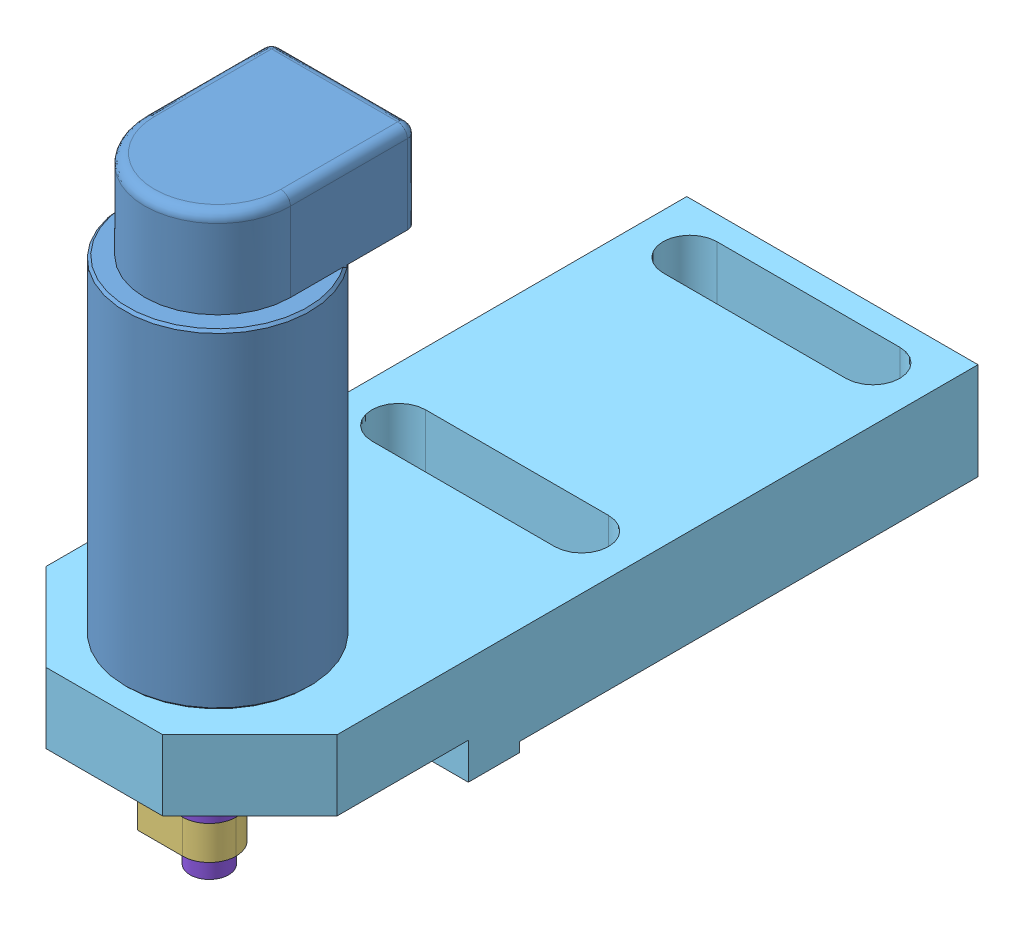
SolidWorks assembly Vibratome Motor Assembly_RevC, configuration Default. Lengths in mm.
Overall size (60 126.02 150).
16 component instances, 8 part files, 33 mates.
Components (placement in the parent):
- [Faulhaber] Series3863MotorwithEncoder-1: [Faulhaber] Series3863MotorwithEncoder [Default] at (-5.4696 226.7867 174.3835) x (1 0 0) z (0 0 -1) size (38 110.4 45.1)
- MotorEshaft-1: MotorEshaft [Default] at (-5.4696 113.4642 187.2942) x (-0.065971 0 0.997822) z (-0.997822 0 -0.065971) size (12.7 33.5 12.7)
- Motor Coupler Rev C-1: Motor Coupler Rev C [Default] at (-11.5224 108.3767 188.0924) x (0 0 1) z (-1 0 0) size (11 7 23)
- 92695A105_HIGH HOLD CONE POINT SET SCREW-5: 92695A105_HIGH HOLD CONE POINT SET SCREW [92695A105] at (-5.7723 130.4642 191.8717) x (-0.332021 -0.943016 -0.021952) z (-0.065971 0 0.997822) size (3.29 2.88 3.42)
- 92695A105_HIGH HOLD CONE POINT SET SCREW-7: 92695A105_HIGH HOLD CONE POINT SET SCREW [92695A105] at (-5.7723 120.4642 191.8717) x (-0.953617 0.294347 -0.063049) z (-0.065971 0 0.997822) size (3.29 2.88 3.42)
- 92695A105_HIGH HOLD CONE POINT SET SCREW-8: 92695A105_HIGH HOLD CONE POINT SET SCREW [92695A105] at (-5.167 130.4642 182.7167) x (0.850692 0.522647 0.056244) z (0.065971 0 -0.997822) size (3.29 2.88 3.42)
- 92695A105_HIGH HOLD CONE POINT SET SCREW-6: 92695A105_HIGH HOLD CONE POINT SET SCREW [92695A105] at (-5.167 120.4642 182.7167) x (0.079659 -0.996808 0.005267) z (0.065971 0 -0.997822) size (3.29 2.88 3.42)
- Motor Holder Redesign-1: Motor Holder Redesign [Default] at (-5.4696 120.6867 134.7942) size (60 22 150)
- 91290A113_BLACK-OXIDE CLASS 12.9 SOCKET HEAD CAP SCREW-8: 91290A113_BLACK-OXIDE CLASS 12.9 SOCKET HEAD CAP SCREW [91290A113] at (-14.9959 143.1867 192.7942) x (0.591518 0 0.806292) z (0 1 0) size (5.5 5.5 11.2)
- 91290A113_BLACK-OXIDE CLASS 12.9 SOCKET HEAD CAP SCREW-7: 91290A113_BLACK-OXIDE CLASS 12.9 SOCKET HEAD CAP SCREW [91290A113] at (-5.4696 143.1867 198.2942) x (0.591518 0 0.806292) z (0 1 0) size (5.5 5.5 11.2)
- 91290A113_BLACK-OXIDE CLASS 12.9 SOCKET HEAD CAP SCREW-11: 91290A113_BLACK-OXIDE CLASS 12.9 SOCKET HEAD CAP SCREW [91290A113] at (-5.4696 143.1867 176.2942) x (0.591518 0 0.806292) z (0 1 0) size (5.5 5.5 11.2)
- 91290A113_BLACK-OXIDE CLASS 12.9 SOCKET HEAD CAP SCREW-9: 91290A113_BLACK-OXIDE CLASS 12.9 SOCKET HEAD CAP SCREW [91290A113] at (4.0567 143.1867 181.7942) x (0.591518 0 0.806292) z (0 1 0) size (5.5 5.5 11.2)
- 91290A113_BLACK-OXIDE CLASS 12.9 SOCKET HEAD CAP SCREW-12: 91290A113_BLACK-OXIDE CLASS 12.9 SOCKET HEAD CAP SCREW [91290A113] at (-14.9959 143.1867 181.7942) x (0.591518 0 0.806292) z (0 1 0) size (5.5 5.5 11.2)
- 91290A113_BLACK-OXIDE CLASS 12.9 SOCKET HEAD CAP SCREW-10: 91290A113_BLACK-OXIDE CLASS 12.9 SOCKET HEAD CAP SCREW [91290A113] at (4.0567 143.1867 192.7942) x (0.591518 0 0.806292) z (0 1 0) size (5.5 5.5 11.2)
- 2706T280_ULTRA-LOW-FRICTION DRY-RUNNING SLEEVE BEARING-1: 2706T280_ULTRA-LOW-FRICTION DRY-RUNNING SLEEVE BEARING [2706T28] at (-5.4696 139.1867 187.2942) x (-0.5 0 -0.866025) z (-0.866025 0 0.5) size (22.23 19.05 22.23)
- 2706T120_ULTRA-LOW-FRICTION DRY-RUNNING SLEEVE BEARING-1: 2706T120_ULTRA-LOW-FRICTION DRY-RUNNING SLEEVE BEARING [2706T12] at (-5.5224 113.4642 188.0924) x (-0.837169 0 -0.546944) z (-0.546944 0 0.837169) size (11.11 12.7 11.11)
Mates (geometry in assembly coordinates):
- Parallel2: parallel aligned: plane of ? through (0.0346 -20.2044 16.1114) normal (0 0 1); plane of assembly through (0 0 0) normal (0 0 1)
- Concentric4: concentric aligned: cylinder of MotorEshaft-1 through (-5.8885 130.4642 193.6304) axis (-0.065971 0 0.997822) radius 1.1303; circle of 92695A105_HIGH HOLD CONE POINT SET SCREW-5
- Concentric5: concentric aligned: cylinder of MotorEshaft-1 through (-5.8885 120.4642 193.6304) axis (-0.065971 0 0.997822) radius 1.1303; circle of 92695A105_HIGH HOLD CONE POINT SET SCREW-7
- Concentric6: concentric anti-aligned: cylinder of MotorEshaft-1 through (-5.8885 120.4642 193.6304) axis (-0.065971 0 0.997822) radius 1.1303; circle of 92695A105_HIGH HOLD CONE POINT SET SCREW-6
- Concentric7: concentric anti-aligned: circle of 92695A105_HIGH HOLD CONE POINT SET SCREW-5; circle of 92695A105_HIGH HOLD CONE POINT SET SCREW-8
- Concentric9: concentric anti-aligned: cylinder of Motor Holder Redesign-1 through (-14.9959 126.1867 192.7942) axis (0 -1 0) radius 2.75; cylinder of 91290A113_BLACK-OXIDE CLASS 12.9 SOCKET HEAD CAP SCREW-8 through (-14.9959 132.1867 192.7942) axis (0 1 0) radius 2.75
- Coincident12: coincident anti-aligned: plane of Motor Holder Redesign-1 through (-13.5459 135.1867 192.7942) normal (0 -1 0); plane of 91290A113_BLACK-OXIDE CLASS 12.9 SOCKET HEAD CAP SCREW-8 through (-14.9959 135.1867 192.7942) normal (0 1 0)
- Concentric10: concentric anti-aligned: cylinder of Motor Holder Redesign-1 through (-5.4696 126.1867 198.2942) axis (0 -1 0) radius 2.75; cylinder of 91290A113_BLACK-OXIDE CLASS 12.9 SOCKET HEAD CAP SCREW-7 through (-5.4696 132.1867 198.2942) axis (0 1 0) radius 2.75
- Concentric11: concentric anti-aligned: cylinder of Motor Holder Redesign-1 through (4.0567 126.1867 192.7942) axis (0 -1 0) radius 2.75; cylinder of 91290A113_BLACK-OXIDE CLASS 12.9 SOCKET HEAD CAP SCREW-10 through (4.0567 132.1867 192.7942) axis (0 1 0) radius 2.75
- Concentric12: concentric anti-aligned: cylinder of Motor Holder Redesign-1 through (4.0567 126.1867 181.7942) axis (0 -1 0) radius 2.75; cylinder of 91290A113_BLACK-OXIDE CLASS 12.9 SOCKET HEAD CAP SCREW-9 through (4.0567 132.1867 181.7942) axis (0 1 0) radius 2.75
- Concentric13: concentric anti-aligned: cylinder of Motor Holder Redesign-1 through (-5.4696 126.1867 176.2942) axis (0 -1 0) radius 2.75; cylinder of 91290A113_BLACK-OXIDE CLASS 12.9 SOCKET HEAD CAP SCREW-11 through (-5.4696 132.1867 176.2942) axis (0 1 0) radius 2.75
- Concentric14: concentric anti-aligned: cylinder of Motor Holder Redesign-1 through (-14.9959 126.1867 181.7942) axis (0 -1 0) radius 2.75; cylinder of 91290A113_BLACK-OXIDE CLASS 12.9 SOCKET HEAD CAP SCREW-12 through (-14.9959 132.1867 181.7942) axis (0 1 0) radius 2.75
- Coincident13: coincident aligned: plane of 91290A113_BLACK-OXIDE CLASS 12.9 SOCKET HEAD CAP SCREW-11 through (-5.4696 132.1867 176.2942) normal (0 -1 0); plane of 91290A113_BLACK-OXIDE CLASS 12.9 SOCKET HEAD CAP SCREW-12 through (-14.9959 132.1867 181.7942) normal (0 -1 0)
- Coincident14: coincident aligned: plane of 91290A113_BLACK-OXIDE CLASS 12.9 SOCKET HEAD CAP SCREW-9 through (4.0567 132.1867 181.7942) normal (0 -1 0); plane of 91290A113_BLACK-OXIDE CLASS 12.9 SOCKET HEAD CAP SCREW-12 through (-14.9959 132.1867 181.7942) normal (0 -1 0)
- Coincident15: coincident aligned: plane of 91290A113_BLACK-OXIDE CLASS 12.9 SOCKET HEAD CAP SCREW-12 through (-14.9959 132.1867 181.7942) normal (0 -1 0); plane of 91290A113_BLACK-OXIDE CLASS 12.9 SOCKET HEAD CAP SCREW-10 through (4.0567 132.1867 192.7942) normal (0 -1 0)
- Coincident17: coincident aligned: plane of 91290A113_BLACK-OXIDE CLASS 12.9 SOCKET HEAD CAP SCREW-7 through (-5.4696 132.1867 198.2942) normal (0 -1 0); plane of 91290A113_BLACK-OXIDE CLASS 12.9 SOCKET HEAD CAP SCREW-12 through (-14.9959 132.1867 181.7942) normal (0 -1 0)
- Coincident18: coincident aligned: plane of 91290A113_BLACK-OXIDE CLASS 12.9 SOCKET HEAD CAP SCREW-8 through (-14.9959 132.1867 192.7942) normal (0 -1 0); plane of 91290A113_BLACK-OXIDE CLASS 12.9 SOCKET HEAD CAP SCREW-7 through (-5.4696 132.1867 198.2942) normal (0 -1 0)
- Coincident19: coincident anti-aligned: plane of Motor Holder Redesign-1 through (2.4679 137.5992 187.2942) normal (0 1 0); plane of 2706T280_ULTRA-LOW-FRICTION DRY-RUNNING SLEEVE BEARING-1 through (-5.4696 137.5992 187.2942) normal (0 -1 0)
- Concentric15: concentric aligned: cylinder of Motor Holder Redesign-1 through (-5.4696 140.6867 187.2942) axis (0 1 0) radius 7.9375; cylinder of 2706T280_ULTRA-LOW-FRICTION DRY-RUNNING SLEEVE BEARING-1 through (-5.4696 120.1367 187.2942) axis (0 1 0) radius 6.35
- Concentric16: concentric anti-aligned: cylinder of Motor Holder Redesign-1 through (-5.4696 126.1867 176.2942) axis (0 -1 0) radius 1.45; cylinder of 2706T280_ULTRA-LOW-FRICTION DRY-RUNNING SLEEVE BEARING-1 through (-5.4696 139.1867 176.2942) axis (0 1 0) radius 1.7
- Distance5: distance = 17.85 mm: line of assembly; plane of Motor Holder Redesign-1 through (-35.4696 126.1867 164.7942) normal (0 -1 0)
- Concentric18: concentric aligned: cylinder of [Faulhaber] Series3863MotorwithEncoder-1 through (-5.4696 116.3867 187.2942) axis (0 1 0) radius 3; cylinder of MotorEshaft-1 through (-5.4696 116.3642 187.2942) axis (0 1 0) radius 3
- Tangent1: tangent anti-aligned: cylinder of [Faulhaber] Series3863MotorwithEncoder-1 through (-5.4696 116.3867 187.2942) axis (0 1 0) radius 3; plane of 92695A105_HIGH HOLD CONE POINT SET SCREW-5 through (-5.4935 130.4027 190.2992) normal (0.065971 0 -0.997822)
- Tangent2: tangent anti-aligned: cylinder of MotorEshaft-1 through (-5.4696 116.3642 187.2942) axis (0 1 0) radius 3; plane of 92695A105_HIGH HOLD CONE POINT SET SCREW-7 through (-5.7218 120.2875 190.2841) normal (0.065971 0 -0.997822)
- Tangent3: tangent anti-aligned: cylinder of MotorEshaft-1 through (-5.4696 116.3642 187.2942) axis (0 1 0) radius 3; plane of 92695A105_HIGH HOLD CONE POINT SET SCREW-6 through (-5.4556 120.4495 184.2886) normal (-0.065971 0 0.997822)
- Tangent4: tangent anti-aligned: cylinder of [Faulhaber] Series3863MotorwithEncoder-1 through (-5.4696 116.3867 187.2942) axis (0 1 0) radius 3; plane of 92695A105_HIGH HOLD CONE POINT SET SCREW-8 through (-5.1753 130.3066 184.3071) normal (-0.065971 0 0.997822)
- Coincident26: coincident anti-aligned: plane of [Faulhaber] Series3863MotorwithEncoder-1 through (-5.4696 140.6867 186.4335) normal (0 -1 0); plane of Motor Holder Redesign-1 through (-5.4696 140.6867 134.7942) normal (0 1 0)
- Concentric19: concentric anti-aligned: cylinder of MotorEshaft-1 through (-5.4696 137.9642 187.2942) axis (0 -1 0) radius 6.35; cylinder of 2706T280_ULTRA-LOW-FRICTION DRY-RUNNING SLEEVE BEARING-1 through (-5.4696 120.1367 187.2942) axis (0 1 0) radius 6.35
- Parallel7: parallel aligned: plane of [Faulhaber] Series3863MotorwithEncoder-1 through (-18.4696 208.4867 160.3335) normal (0 0 -1); plane of Motor Holder Redesign-1 through (-35.4696 140.6867 59.7942) normal (0 0 -1)
- Concentric20: concentric aligned: cylinder of MotorEshaft-1 through (-5.5224 104.4642 188.0924) axis (0 1 0) radius 2.3813; cylinder of Motor Coupler Rev C-1 through (-5.5224 104.8767 188.0924) axis (0 1 0) radius 3.9688
- Concentric21: concentric aligned: cylinder of Motor Coupler Rev C-1 through (-5.5224 104.8767 188.0924) axis (0 1 0) radius 3.9688; cylinder of 2706T120_ULTRA-LOW-FRICTION DRY-RUNNING SLEEVE BEARING-1 through (-5.5224 100.7642 188.0924) axis (0 1 0) radius 3.9688
- Coincident28: coincident anti-aligned: plane of Motor Coupler Rev C-1 through (-23.0224 111.8767 193.5924) normal (0 1 0); plane of 2706T120_ULTRA-LOW-FRICTION DRY-RUNNING SLEEVE BEARING-1 through (-5.5224 111.8767 188.0924) normal (0 -1 0)
- Coincident29: coincident anti-aligned: plane of MotorEshaft-1 through (-5.4696 113.4642 187.2942) normal (0 -1 0); plane of 2706T120_ULTRA-LOW-FRICTION DRY-RUNNING SLEEVE BEARING-1 through (-5.5224 113.4642 188.0924) normal (0 1 0)
